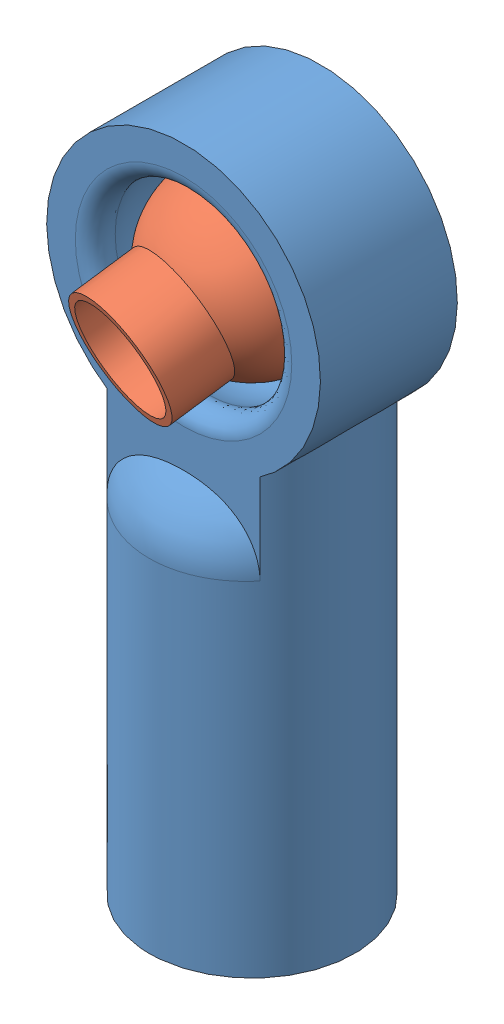
SolidWorks assembly Ball Joint, configuration Default. Lengths in mm.
Overall size (8 20 9.06).
2 component instances, 2 part files, 2 mates.
Components (placement in the parent):
- Ball Joint Steer-1: Ball Joint Steer [Default] at (9.2195 3.7861 18.9447) size (8 20 6)
- Ball Joint Steer 1-1: Ball Joint Steer 1 [Default] at (9.2195 19.7861 18.9447) x (0.159606 -0.940649 -0.299509) z (-0.168728 -0.324928 0.930566) size (5 5 7)
Mates (geometry in assembly coordinates):
- Concentric1: concentric: sphere of Ball Joint Steer-1; sphere of Ball Joint Steer 1-1
- LimitAngle1: limit planar angle = 0.374841 rad aligned: plane of Ball Joint Steer 1-1 through (9.2195 19.7861 18.9447) normal (-0.168728 -0.324928 0.930566); plane of Ball Joint Steer-1 through (9.2195 3.7861 18.9447) normal (0 0 1)
